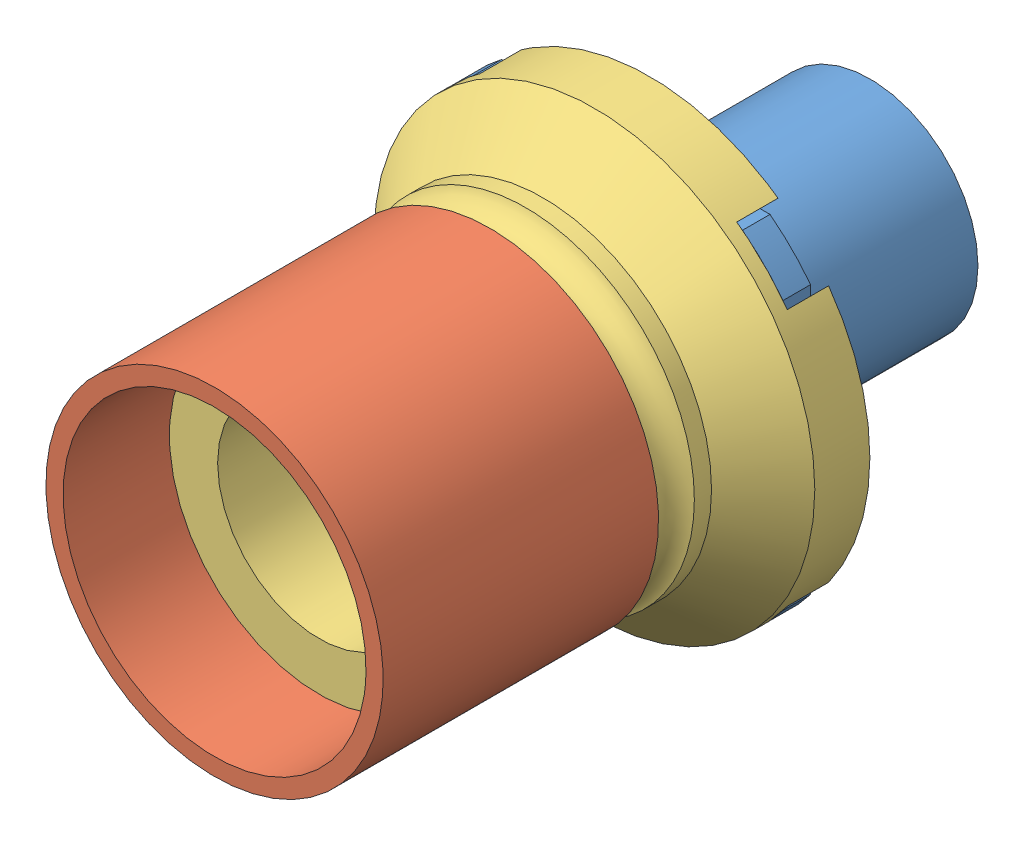
SolidWorks assembly Unten, configuration Standard. Lengths in mm.
Overall size (32 32 47.6).
3 component instances, 3 part files, 5 mates.
Components (placement in the parent):
- N-Stecker-1: N-Stecker [Standard] at (2.7545 -0.0307 31.025) size (25.38 25.38 28.05)
- rohr-1: rohr [Standard] at (2.7545 -0.0307 41.6208) x (0.996373 -0.085093 0) z (0 0 1) size (24.5 24.5 20)
- Stopen-Unten-1: Stopen-Unten [Standard] at (2.7545 -0.0307 54.025) x (-1 0 0) z (0 0 -1) size (32 32 24)
Mates (geometry in assembly coordinates):
- Deckungsgleich1: coincident anti-aligned: plane of N-Stecker-1 through (2.7545 -0.0307 33.025) normal (0 0 1); plane of Stopen-Unten-1 through (2.7545 -0.0307 33.025) normal (0 0 -1)
- Konzentrisch3: concentric anti-aligned: cylinder of N-Stecker-1 through (2.7545 -0.0307 33.925) axis (0 0 -1) radius 7.27; cylinder of Stopen-Unten-1 through (2.7545 -0.0307 39.025) axis (0 0 1) radius 7.375
- Parallel2: parallel anti-aligned: plane of N-Stecker-1 through (12.4994 -12.7207 33.025) normal (0 -1 0); plane of Stopen-Unten-1 through (12.0819 -13.0307 30.025) normal (0 1 0)
- Konzentrisch4: concentric anti-aligned: cylinder of rohr-1 through (2.7545 -0.0307 61.6208) axis (0 0 -1) radius 11; cylinder of Stopen-Unten-1 through (2.7545 -0.0307 39.025) axis (0 0 1) radius 10.875
- Tangential1: tangent: circle of rohr-1; torus of Stopen-Unten-1
